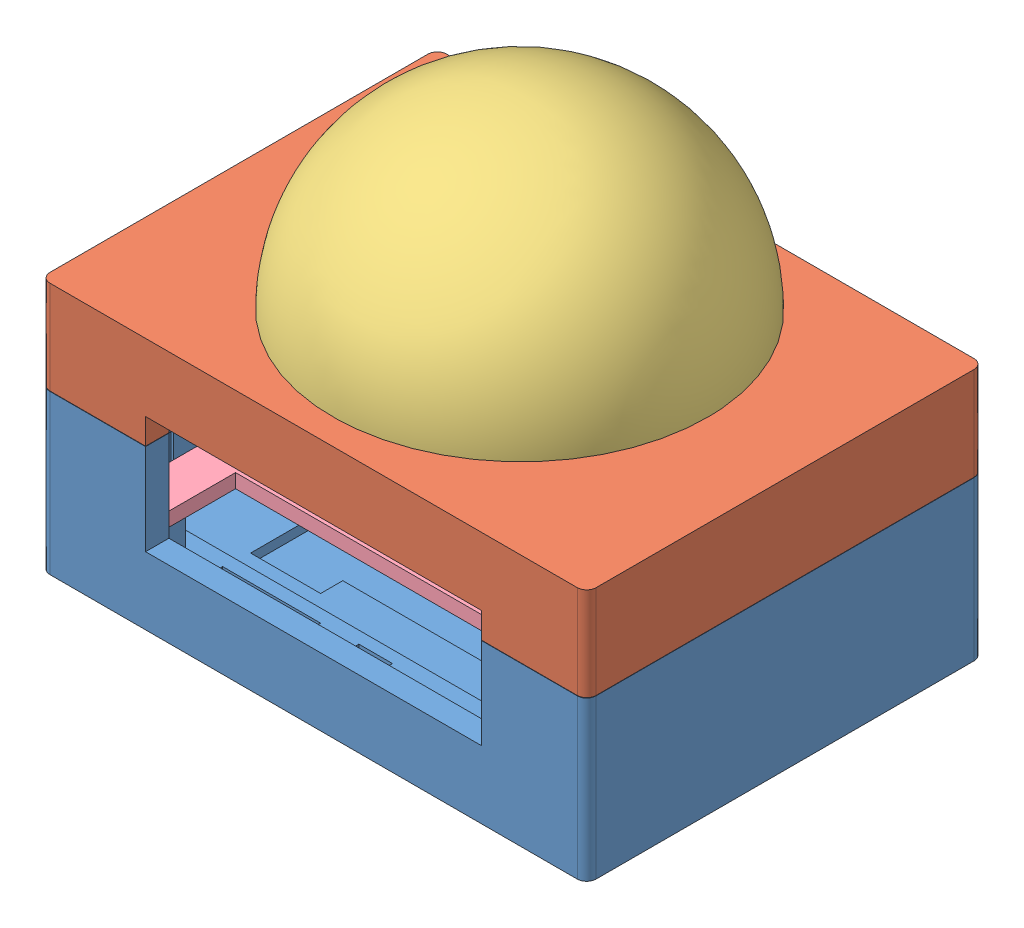
SolidWorks assembly Assem4, configuration Default. Lengths in mm.
Overall size (117.01 96.5 85).
5 component instances, 5 part files, 0 mates.
Components (placement in the parent):
- Test-1: Test [Default] at (46.2922 36.5117 93.5515) size (117 34 85)
- TestMiddle-1: TestMiddle [Default] at (46.3008 70.5953 93.5554) size (117 20 85)
- TestUpper-3: TestUpper [Default] at (47.3285 92.7482 92.9636) x (-0.999627 -0.000462 0.027304) z (-0.0273 -0.006257 -0.999608) size (80 50 80)
- TestCover-1: TestCover [Default] at (49.048 52.5609 94.0255) size (95 8 76.35)
- TestCharge-1: TestCharge [Default] at (46.4659 58.7557 73.2136) size (43 2.5 14)
